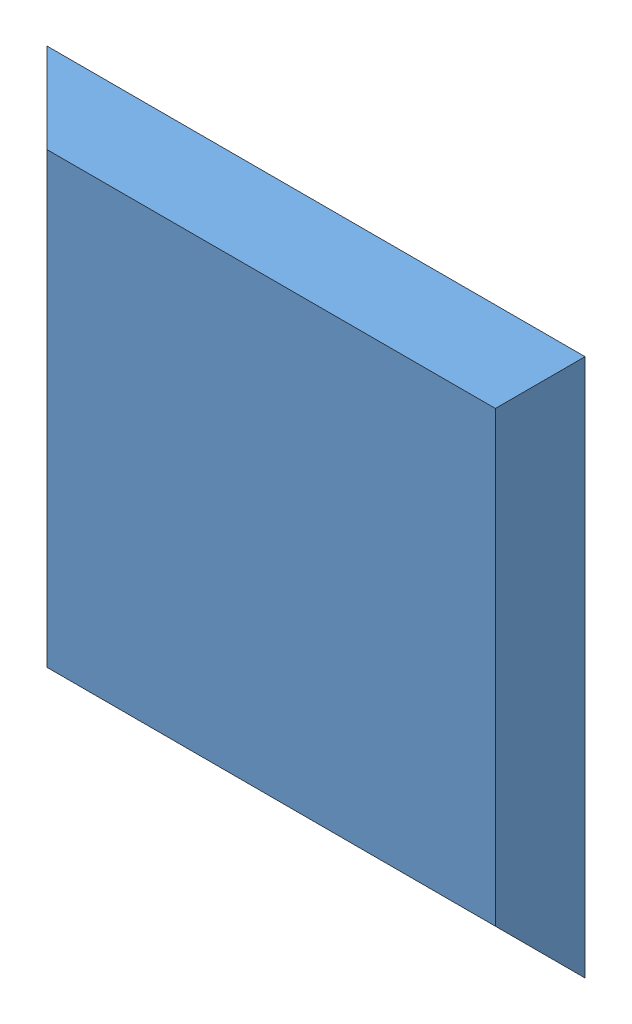
SolidWorks assembly MagnetRoundFaceAssem, configuration Default. Lengths in mm.
Overall size (76.2 76.2 6.35).
9 component instances, 2 part files, 16 mates.
Components (placement in the parent):
- MagnetRoundFace-7: MagnetRoundFace [Default] at (-1.5201 21.7196 86.5614) size (76.2 76.2 6.35)
- round magnet-13: round magnet [Default] at (9.9099 64.8996 86.5614) size (5 5 3)
- round magnet-16: round magnet [Default] at (63.2499 64.8996 86.5614) size (5 5 3)
- round magnet-17: round magnet [Default] at (41.6599 86.4896 86.5614) size (5 5 3)
- round magnet-18: round magnet [Default] at (31.4999 86.4896 86.5614) size (5 5 3)
- round magnet-19: round magnet [Default] at (41.6599 33.1496 86.5614) size (5 5 3)
- round magnet-21: round magnet [Default] at (63.2499 54.7396 86.5614) size (5 5 3)
- round magnet-22: round magnet [Default] at (31.4999 33.1496 86.5614) size (5 5 3)
- round magnet-24: round magnet [Default] at (9.9099 54.7396 89.5614) x (0.413628 0.910446 0) z (0 0 -1) size (5 5 3)
Mates (geometry in assembly coordinates):
- Coincident6: coincident anti-aligned: plane of MagnetRoundFace-7 through (9.9099 64.8996 89.5614) normal (0 0 -1); plane of round magnet-13 through (9.9099 64.8996 89.5614) normal (0 0 1)
- Concentric2: concentric aligned: cylinder of MagnetRoundFace-7 through (9.9099 64.8996 89.5614) axis (0 0 -1) radius 3.5; cylinder of round magnet-13 through (9.9099 64.8996 89.5614) axis (0 0 -1) radius 2.5
- Coincident8: coincident anti-aligned: plane of MagnetRoundFace-7 through (9.9099 54.7396 89.5614) normal (0 0 -1); plane of round magnet-24 through (9.9099 54.7396 89.5614) normal (0 0 1)
- Concentric4: concentric anti-aligned: cylinder of MagnetRoundFace-7 through (9.9099 54.7396 89.5614) axis (0 0 -1) radius 3.5; cylinder of round magnet-24 through (9.9099 54.7396 86.5614) axis (0 0 1) radius 2.5
- Coincident19: coincident anti-aligned: plane of MagnetRoundFace-7 through (31.4999 33.1496 89.5614) normal (0 0 -1); circle of round magnet-22
- Concentric15: concentric aligned: cylinder of MagnetRoundFace-7 through (31.4999 33.1496 89.5614) axis (0 0 -1) radius 3.5; cylinder of round magnet-22 through (31.4999 33.1496 89.5614) axis (0 0 -1) radius 2.5
- Coincident20: coincident anti-aligned: plane of MagnetRoundFace-7 through (41.6599 33.1496 89.5614) normal (0 0 -1); plane of round magnet-19 through (41.6599 33.1496 89.5614) normal (0 0 1)
- Concentric16: concentric aligned: cylinder of MagnetRoundFace-7 through (41.6599 33.1496 89.5614) axis (0 0 -1) radius 3.5; cylinder of round magnet-19 through (41.6599 33.1496 89.5614) axis (0 0 -1) radius 2.5
- Coincident22: coincident anti-aligned: plane of MagnetRoundFace-7 through (63.2499 54.7396 89.5614) normal (0 0 -1); plane of round magnet-21 through (63.2499 54.7396 89.5614) normal (0 0 1)
- Concentric18: concentric aligned: cylinder of MagnetRoundFace-7 through (63.2499 54.7396 89.5614) axis (0 0 -1) radius 3.5; cylinder of round magnet-21 through (63.2499 54.7396 89.5614) axis (0 0 -1) radius 2.5
- Coincident23: coincident anti-aligned: plane of MagnetRoundFace-7 through (63.2499 64.8996 89.5614) normal (0 0 -1); plane of round magnet-16 through (63.2499 64.8996 89.5614) normal (0 0 1)
- Concentric19: concentric aligned: cylinder of MagnetRoundFace-7 through (63.2499 64.8996 89.5614) axis (0 0 -1) radius 3.5; cylinder of round magnet-16 through (63.2499 64.8996 89.5614) axis (0 0 -1) radius 2.5
- Coincident25: coincident anti-aligned: plane of MagnetRoundFace-7 through (41.6599 86.4896 89.5614) normal (0 0 -1); plane of round magnet-17 through (41.6599 86.4896 89.5614) normal (0 0 1)
- Concentric21: concentric aligned: cylinder of MagnetRoundFace-7 through (41.6599 86.4896 89.5614) axis (0 0 -1) radius 3.5; cylinder of round magnet-17 through (41.6599 86.4896 89.5614) axis (0 0 -1) radius 2.5
- Coincident26: coincident anti-aligned: plane of MagnetRoundFace-7 through (31.4999 86.4896 89.5614) normal (0 0 -1); plane of round magnet-18 through (31.4999 86.4896 89.5614) normal (0 0 1)
- Concentric22: concentric aligned: cylinder of MagnetRoundFace-7 through (31.4999 86.4896 89.5614) axis (0 0 -1) radius 3.5; cylinder of round magnet-18 through (31.4999 86.4896 89.5614) axis (0 0 -1) radius 2.5
